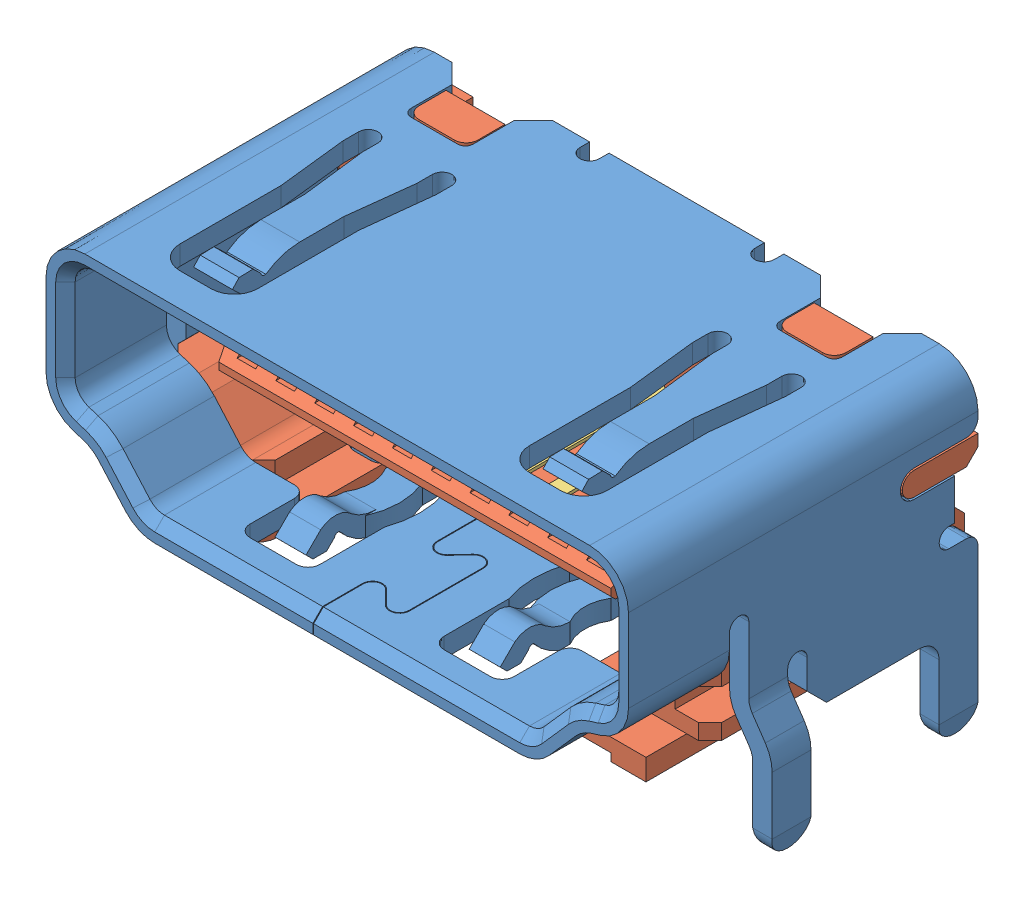
SolidWorks assembly raspberry_pi__HDMI_socket, configuration Default. Lengths in mm.
Overall size (16.2 8 9.9).
21 component instances, 4 part files, 0 mates.
Components (placement in the parent):
- raspberry_pi__HDMI_socket_cover-1: raspberry_pi__HDMI_socket_cover [Default] at (-20 0 0) size (16.2 8 9)
- raspberry_pi__HDMI_socket_inside-1: raspberry_pi__HDMI_socket_inside [Default] at (-20 0 0) size (15 6.1 7.6)
- raspberry_pi__HDMI_socket_large_pin-1: raspberry_pi__HDMI_socket_large_pin [Valor predeterminado] at (-201.7661 0.45 76.5103) x (0 0 -1) z (0 -1 0) size (7.55 0.65 3.84)
- raspberry_pi__HDMI_socket_small_pin-1: raspberry_pi__HDMI_socket_small_pin [Valor predeterminado] at (-202.2661 -0.25 76.5103) x (0 0 -1) z (0 -1 0) size (7.55 0.65 3.08)
- raspberry_pi__HDMI_socket_large_pin-2: raspberry_pi__HDMI_socket_large_pin [Valor predeterminado] at (-202.7661 0.45 76.5103) x (0 0 -1) z (0 -1 0) size (7.55 0.65 3.84)
- raspberry_pi__HDMI_socket_large_pin-3: raspberry_pi__HDMI_socket_large_pin [Valor predeterminado] at (-203.7661 0.45 76.5103) x (0 0 -1) z (0 -1 0) size (7.55 0.65 3.84)
- raspberry_pi__HDMI_socket_large_pin-4: raspberry_pi__HDMI_socket_large_pin [Valor predeterminado] at (-204.7661 0.45 76.5103) x (0 0 -1) z (0 -1 0) size (7.55 0.65 3.84)
- raspberry_pi__HDMI_socket_large_pin-5: raspberry_pi__HDMI_socket_large_pin [Valor predeterminado] at (-205.7661 0.45 76.5103) x (0 0 -1) z (0 -1 0) size (7.55 0.65 3.84)
- raspberry_pi__HDMI_socket_large_pin-6: raspberry_pi__HDMI_socket_large_pin [Valor predeterminado] at (-206.7661 0.45 76.5103) x (0 0 -1) z (0 -1 0) size (7.55 0.65 3.84)
- raspberry_pi__HDMI_socket_large_pin-7: raspberry_pi__HDMI_socket_large_pin [Valor predeterminado] at (-207.7661 0.45 76.5103) x (0 0 -1) z (0 -1 0) size (7.55 0.65 3.84)
- raspberry_pi__HDMI_socket_large_pin-8: raspberry_pi__HDMI_socket_large_pin [Valor predeterminado] at (-208.7661 0.45 76.5103) x (0 0 -1) z (0 -1 0) size (7.55 0.65 3.84)
- raspberry_pi__HDMI_socket_large_pin-9: raspberry_pi__HDMI_socket_large_pin [Valor predeterminado] at (-209.7661 0.45 76.5103) x (0 0 -1) z (0 -1 0) size (7.55 0.65 3.84)
- raspberry_pi__HDMI_socket_large_pin-10: raspberry_pi__HDMI_socket_large_pin [Valor predeterminado] at (-210.7661 0.45 76.5103) x (0 0 -1) z (0 -1 0) size (7.55 0.65 3.84)
- raspberry_pi__HDMI_socket_small_pin-2: raspberry_pi__HDMI_socket_small_pin [Valor predeterminado] at (-203.2661 -0.25 76.5103) x (0 0 -1) z (0 -1 0) size (7.55 0.65 3.08)
- raspberry_pi__HDMI_socket_small_pin-3: raspberry_pi__HDMI_socket_small_pin [Valor predeterminado] at (-204.2661 -0.25 76.5103) x (0 0 -1) z (0 -1 0) size (7.55 0.65 3.08)
- raspberry_pi__HDMI_socket_small_pin-4: raspberry_pi__HDMI_socket_small_pin [Valor predeterminado] at (-205.2661 -0.25 76.5103) x (0 0 -1) z (0 -1 0) size (7.55 0.65 3.08)
- raspberry_pi__HDMI_socket_small_pin-5: raspberry_pi__HDMI_socket_small_pin [Valor predeterminado] at (-206.2661 -0.25 76.5103) x (0 0 -1) z (0 -1 0) size (7.55 0.65 3.08)
- raspberry_pi__HDMI_socket_small_pin-6: raspberry_pi__HDMI_socket_small_pin [Valor predeterminado] at (-207.2661 -0.25 76.5103) x (0 0 -1) z (0 -1 0) size (7.55 0.65 3.08)
- raspberry_pi__HDMI_socket_small_pin-7: raspberry_pi__HDMI_socket_small_pin [Valor predeterminado] at (-208.2661 -0.25 76.5103) x (0 0 -1) z (0 -1 0) size (7.55 0.65 3.08)
- raspberry_pi__HDMI_socket_small_pin-8: raspberry_pi__HDMI_socket_small_pin [Valor predeterminado] at (-209.2661 -0.25 76.5103) x (0 0 -1) z (0 -1 0) size (7.55 0.65 3.08)
- raspberry_pi__HDMI_socket_small_pin-9: raspberry_pi__HDMI_socket_small_pin [Valor predeterminado] at (-210.2661 -0.25 76.5103) x (0 0 -1) z (0 -1 0) size (7.55 0.65 3.08)
